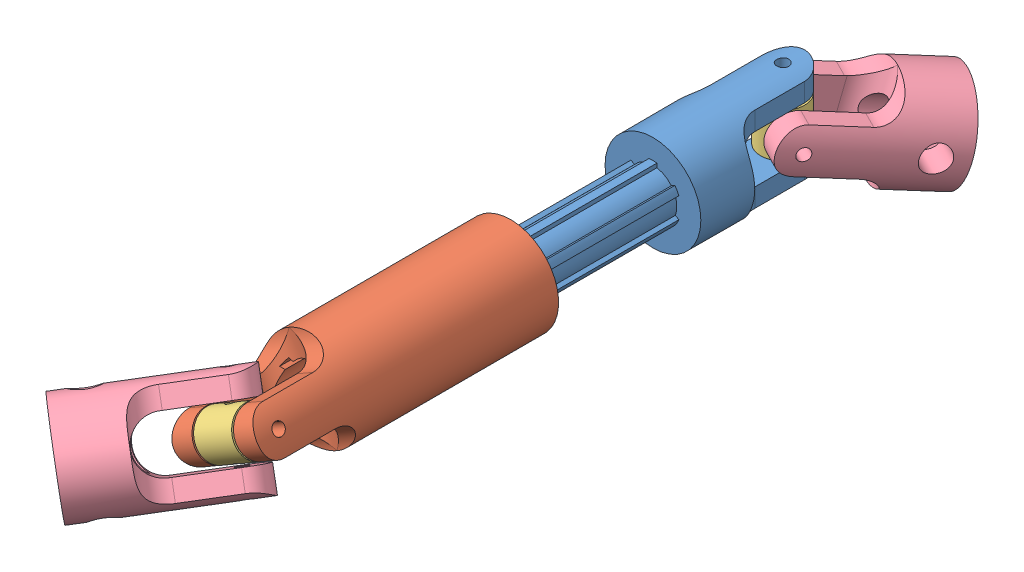
SolidWorks assembly 万向节装配体, configuration 默认. Lengths in mm.
Overall size (32.68 19.76 107.52).
6 component instances, 4 part files, 10 mates.
Components (placement in the parent):
- 可伸缩万向节2-1: 可伸缩万向节2 [默认] at (-54.0006 12.1231 -0.5466) size (12.58 12 45)
- 可伸缩万向节3-1: 可伸缩万向节3 [默认] at (-54.0006 12.1231 73.2701) x (-0.5 0.866025 0) z (0 0 -1) size (12.58 12 37)
- 万向节中间球-1: 万向节中间球 [默认] at (-54.0006 9.3731 2.2034) x (-0.451554 0 0.892244) z (0 1 0) size (5.5 5.5 5.5)
- 万向节中间球-2: 万向节中间球 [默认] at (-56.3822 10.7481 70.5201) x (0.140777 -0.243832 -0.959546) z (0.866025 0.5 0) size (5.5 5.5 5.5)
- 可伸缩万向节1-1: 可伸缩万向节1 [默认] at (-55.2012 12.8253 4.5757) x (0.115312 0.966844 -0.227849) z (0.436582 -0.255366 -0.862661) size (12.58 12 23.09)
- 可伸缩万向节1-2: 可伸缩万向节1 [默认] at (-52.2032 12.4652 68.4671) x (0.585325 0.542191 0.602846) z (-0.653616 -0.124429 0.746528) size (12.58 12 23.09)
Mates (geometry in assembly coordinates):
- 同心1: concentric: cylinder of 可伸缩万向节2-1 through (-54.0006 2.6231 2.2034) axis (0 1 0) radius 0.75; cylinder of 万向节中间球-1 through (-54.0006 14.8731 2.2034) axis (0 -1 0) radius 0.75
- 距离1: distance = 0.25 mm: plane of 万向节中间球-1 through (-54.0006 9.3731 2.2034) normal (0 -1 0); plane of 可伸缩万向节2-1 through (-63.5006 9.1231 -0.5466) normal (0 1 0)
- 重合2: coincident: cylinder of 万向节中间球-1 through (-56.4543 12.1231 0.9616) axis (0.892244 0 0.451554) radius 0.75; circle of 可伸缩万向节1-1
- 同心2: concentric: cylinder of 可伸缩万向节2-1 through (-54.0006 12.1231 44.4534) axis (0 0 -1) radius 3; cylinder of 可伸缩万向节3-1 through (-54.0006 12.1231 67.2701) axis (0 0 -1) radius 3
- LimitDistance1: limit distance = 17.8167 mm: plane of 可伸缩万向节3-1 through (-54.0006 12.1231 36.2701) normal (0 0 -1); plane of 可伸缩万向节2-1 through (-54.0006 12.1231 18.4534) normal (0 0 1)
- 同心3: concentric: cylinder of 可伸缩万向节3-1 through (-62.2279 7.3731 70.5201) axis (0.866025 0.5 0) radius 0.75; cylinder of 万向节中间球-2 through (-51.6191 13.4981 70.5201) axis (-0.866025 -0.5 0) radius 0.75
- 距离4: distance = 0.25 mm: plane of 万向节中间球-2 through (-51.6191 13.4981 70.5201) normal (0.866025 0.5 0); plane of 可伸缩万向节3-1 through (-46.6525 5.3958 64.0201) normal (-0.866025 -0.5 0)
- 同心4: concentric: cylinder of 万向节中间球-2 through (-52.6812 9.8378 71.2943) axis (-0.479773 0.830991 -0.281553) radius 0.75; cylinder of 可伸缩万向节1-2 through (-49.4428 4.2287 73.1948) axis (-0.479773 0.830991 -0.281553) radius 0.75
- 距离6: distance = 0.25 mm: plane of 可伸缩万向节1-2 through (-56.3244 4.8215 63.5847) normal (-0.479773 0.830991 -0.281553); cylinder of 万向节中间球-2 through (-51.6191 13.4981 70.5201) axis (-0.866025 -0.5 0) radius 2.75
- 距离8: distance = 0.25 mm: cylinder of 万向节中间球-1 through (-54.0006 14.8731 2.2034) axis (0 -1 0) radius 2.75; plane of 可伸缩万向节1-1 through (-58.9734 3.6403 5.3856) normal (0.892244 0 0.451554)
